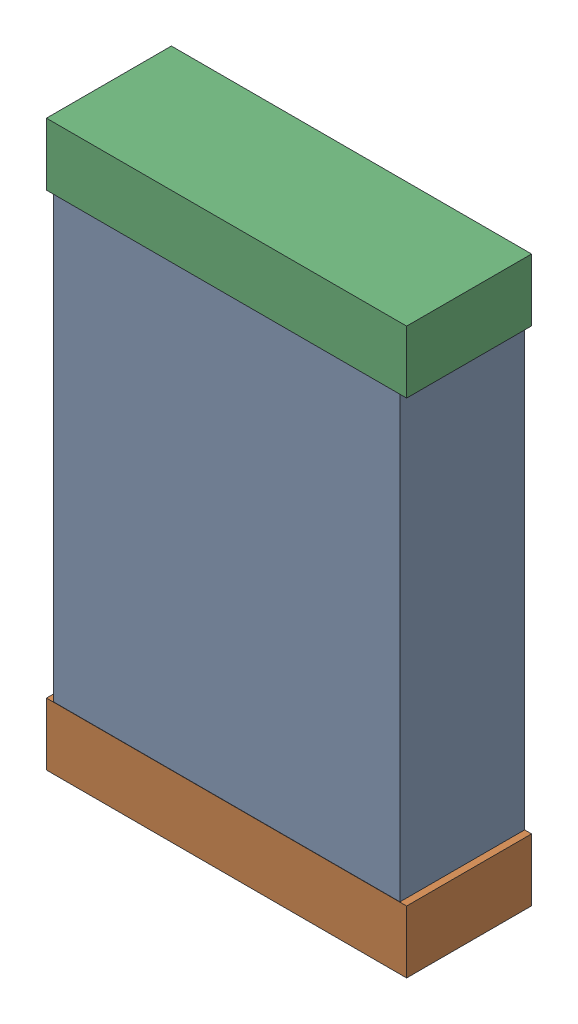
SolidWorks assembly C57, configuration Default. Lengths in mm.
Overall size (1.3 2.04 0.45).
6 component instances, 2 part files, 0 mates.
Components (placement in the parent):
- 740904480-1: 740904480 [Default] at (69.215 27.686 0) size (1.25 2 0.45)
  - Extruded_34-1: Extruded_34 [Default] at origin size (1.25 2 0.45)
- 740902240-1: 740902240 [Default] at (69.215 26.7735 0) size (1.3 0.23 0.45)
  - Extruded_35-1: Extruded_35 [Default] at origin size (1.3 0.23 0.45)
- 740902240-2: 740902240 [Default] at (69.215 28.586 0) size (1.3 0.23 0.45)
  - Extruded_35-1: Extruded_35 [Default] at origin size (1.3 0.23 0.45)
